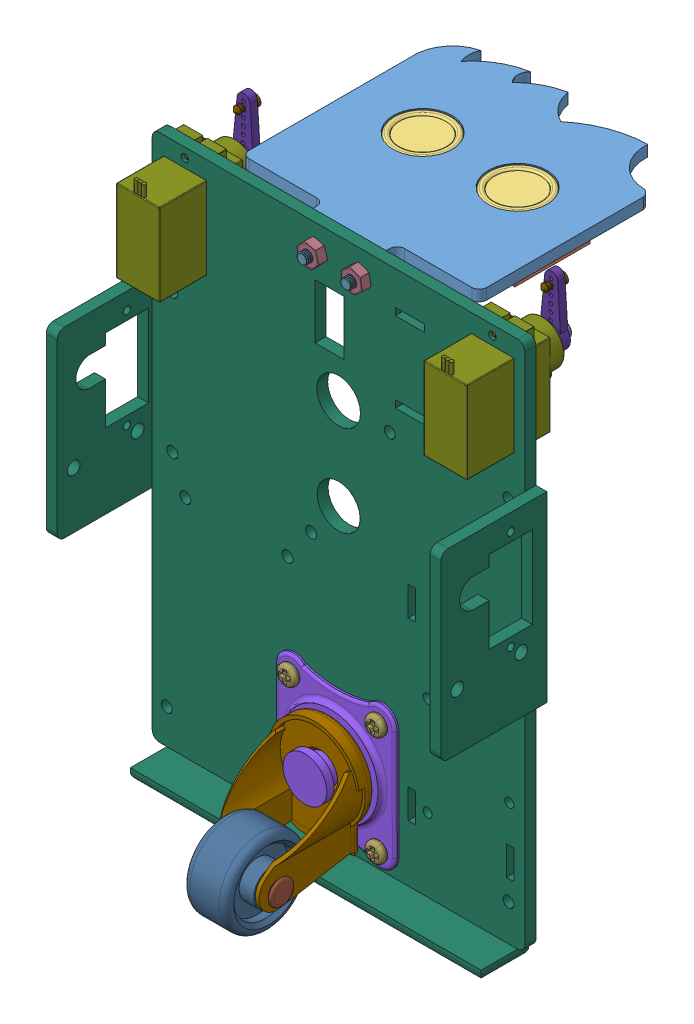
SolidWorks assembly DYOR_3D_PU, configuration Predeterminado. Lengths in mm.
Overall size (108 155.56 103.03).
48 component instances, 19 part files, 12 mates.
Components (placement in the parent):
- Front-1: Front [Predeterminado] at (30.3569 39.5388 1.4932) x (1 0 0) z (0 1 0) size (65 62.44 11)
- HC-SR04 Ping Sensor-1: HC-SR04 Ping Sensor [Default] at (9.418 28.7888 -23.4611) x (0 0 -1) z (0 1 0) size (25.18 45 18.07)
  - PCB-1: PCB [Default] at origin size (20.5 45 1.75)
  - Transducer-1: Transducer [Default] at (0 -13 13.25) x (1 0 0) z (0 -1 0) size (15.88 12 15.88)
  - Transducer-2: Transducer [Default] at (0 13 13.25) x (1 0 0) z (0 -1 0) size (15.88 12 15.88)
  - 3 Pin Header 90 Degree-1: 3 Pin Header 90 Degree [Default] at (8.4275 0 -1.25) x (-1 0 0) z (0 -1 0) size (8 7.82 10)
  - 14 Pin SMT-1: 14 Pin SMT [Default] at (-0.35 -18.5 -0.85) x (0 -1 0) z (1 0 0) size (6 1.6 8.8)
  - 14 Pin SMT-2: 14 Pin SMT [Default] at (0 -0.3826 -0.85) x (1 0 0) z (0 1 0) size (6 1.6 8.8)
  - 14 Pin SMT-3: 14 Pin SMT [Default] at (0 17.5274 -0.85) x (1 0 0) z (0 1 0) size (6 1.6 8.8)
  - Cap1 SMT-1: Cap1 SMT [Default] at (-1.755 7.4774 -0.9689) x (0 1 0) z (-1 0 0) size (4.5 1.84 1.75)
  - Cap1 SMT-2: Cap1 SMT [Default] at (6.835 7.4774 -0.9689) x (0 1 0) z (-1 0 0) size (4.5 1.84 1.75)
  - Cap1 SMT-3: Cap1 SMT [Default] at (-6.835 7.4774 -0.9689) x (0 1 0) z (-1 0 0) size (4.5 1.84 1.75)
  - Cap1 SMT-4: Cap1 SMT [Default] at (4.295 7.4774 -0.9689) x (0 1 0) z (-1 0 0) size (4.5 1.84 1.75)
  - Cap1 SMT-5: Cap1 SMT [Default] at (1.755 7.4774 -0.9689) x (0 1 0) z (-1 0 0) size (4.5 1.84 1.75)
  - Cap1 SMT-6: Cap1 SMT [Default] at (-4.295 7.4774 -0.9689) x (0 1 0) z (-1 0 0) size (4.5 1.84 1.75)
  - HC-SR04 Crystal-1: HC-SR04 Crystal [Default] at (-8.3 0 1.75) x (0 -1 0) z (0 0 1) size (10 3.5 2.7)
- CA-1: CA [Predeterminado] at (-2.2402 -1.1323 0) x (1 0.000939 0) z (0 0 1) size (33 45.94 43.2)
  - Caster Wheel-1: Caster Wheel [Default] at (57.6387 -78.841 57.7572) x (0 1 0) z (-1 0 0) size (45.94 37.59 33)
    - caster holder-1: caster holder [Default] at (-24.0751 44.7184 29.5137) x (1 0 0) z (0 0 -1) size (39 9.27 33)
    - holder-1: holder [Default] at (-1.5751 42.9484 46.0137) x (0 0 1) z (1 0 0) size (25 28.07 31.31)
    - caster wheel-1: caster wheel [Default] at (-15.6961 19.9484 46.0137) x (0.997275 0.073773 0) z (0 0 1) size (23 23 14)
    - Part4-1: Part4 [Default] at (-15.6961 19.9484 55.0137) x (-0.978448 0.206495 0) z (0 0 -1) size (7 7 20)
  - M3x6 Philips Screw-1: M3x6 Philips Screw [Predeterminado] at (23.625 -65.4161 13.5389) size (5.3 5.3 7.81)
  - M3x6 Philips Screw-2: M3x6 Philips Screw [Predeterminado] at (-0.375 -65.4161 13.5389) size (5.3 5.3 7.81)
  - M3x6 Philips Screw-3: M3x6 Philips Screw [Predeterminado] at (-0.375 -95.4161 13.5389) size (5.3 5.3 7.81)
  - M3x6 Philips Screw-4: M3x6 Philips Screw [Predeterminado] at (23.625 -95.4161 13.5389) size (5.3 5.3 7.81)
  - M3 Nut-1: M3 Nut [Predeterminado] at (23.625 -65.4161 11.0389) size (6.27 6.27 2.71)
  - M3 Nut-2: M3 Nut [Predeterminado] at (-0.375 -65.4161 11.0389) size (6.27 6.27 2.71)
  - M3 Nut-3: M3 Nut [Predeterminado] at (-0.375 -95.4161 11.0389) size (6.27 6.27 2.71)
  - M3 Nut-4: M3 Nut [Predeterminado] at (23.625 -95.4161 11.0389) size (6.27 6.27 2.71)
- M3x10 Philips Screw-2: M3x10 Philips Screw [Predeterminado] at (3.418 36.0388 6.5389) x (0.88719 -0.461404 0) z (0 0 -1) size (5.3 5.3 11.8)
- M3x10 Philips Screw-3: M3x10 Philips Screw [Predeterminado] at (15.418 36.0388 6.5389) x (0.471193 -0.88203 0) z (0 0 -1) size (5.3 5.3 11.8)
- M3 Nut-1: M3 Nut [Predeterminado] at (3.418 36.0388 16.5389) x (0.222076 0.975029 0) z (0 0 1) size (6.27 6.27 2.71)
- M3 Nut-2: M3 Nut [Predeterminado] at (15.418 36.0388 11.0389) x (-0.334718 -0.942319 0) z (0 0 -1) size (6.27 6.27 2.71)
- BasePU-1: BasePU [Predeterminado] at (-51.2528 96.5598 9.5389) size (108 147.56 29)
- PU-1: PU [Predeterminado] at (-155.9776 204.2742 -130.283) size (95.94 37.23 33.31)
  - sg90-1: sg90 [Default] at (201.5956 -166.7354 155.7219) x (0 -1 0) z (1 0 0) size (31.9 29.9 11.8)
  - sg90-2: sg90 [Default] at (117.452 -166.7354 155.7219) x (0 -1 0) z (1 0 0) size (31.9 29.9 11.8)
  - SG90 plastic Horn-1: SG90 plastic Horn [Default] at (123.352 -172.6354 127.0219) x (0.017141 0.999853 0) z (-0.999853 0.017141 0) size (19.4 4 7.07)
  - SG90 plastic Horn-2: SG90 plastic Horn [Default] at (207.4956 -172.6354 127.0219) x (0.020276 0.999794 0) z (-0.999794 0.020276 0) size (19.4 4 7.07)
  - M2x6 SelfTap Screw-1: M2x6 SelfTap Screw [Predeterminado] at (207.4956 -164.3354 136.8219) x (-0.923728 -0.383049 0) z (0 0 -1) size (3.4 3.28 6)
  - M2x6 SelfTap Screw-2: M2x6 SelfTap Screw [Predeterminado] at (207.4956 -191.6354 136.3219) x (-0.923728 -0.383049 0) z (0 0 -1) size (3.4 3.28 6)
  - M2x6 SelfTap Screw-3: M2x6 SelfTap Screw [Predeterminado] at (123.352 -164.3354 136.8219) x (-0.993348 0.115149 0) z (0 0 -1) size (3.4 3.28 6)
  - M2x6 SelfTap Screw-4: M2x6 SelfTap Screw [Predeterminado] at (123.352 -191.6354 136.8219) x (-0.923728 -0.383049 0) z (0 0 -1) size (3.4 3.28 6)
  - (M2_3_mm)_90116A007_METRIC 316 SS PAN HEAD PHILLIPS MACHINE SCREW-1: (M2_3_mm)_90116A007_METRIC 316 SS PAN HEAD PHILLIPS MACHINE SCREW [90116A007] at (123.352 -172.6354 127.0219) x (-0.923728 -0.383049 0) z (0 0 -1) size (4 4 4.68)
  - (M2_3_mm)_90116A007_METRIC 316 SS PAN HEAD PHILLIPS MACHINE SCREW-2: (M2_3_mm)_90116A007_METRIC 316 SS PAN HEAD PHILLIPS MACHINE SCREW [90116A007] at (207.4956 -172.6354 127.0219) x (-0.923728 -0.383049 0) z (0 0 -1) size (4 4 4.68)
  - M2x6 SelfTap Screw-5: M2x6 SelfTap Screw [Predeterminado] at (123.352 -160.1354 123.5219) x (-0.923728 -0.383049 0) z (0 0 -1) size (3.4 3.28 6)
  - M2x6 SelfTap Screw-6: M2x6 SelfTap Screw [Predeterminado] at (207.4956 -160.1354 123.5219) x (-0.923728 -0.383049 0) z (0 0 -1) size (3.4 3.28 6)
Mates (geometry in assembly coordinates):
- Concéntrica4: concentric: circle of Front-1; circle of HC-SR04 Ping Sensor-1/Transducer-1
- Concéntrica5: concentric: circle of Front-1; circle of HC-SR04 Ping Sensor-1/Transducer-2
- Coincidente3: coincident: plane of Front-1 through (-2.582 42.5388 8.5374) normal (0 1 0); plane of HC-SR04 Ping Sensor-1/Transducer-1 through (22.418 42.5388 -31.4011) normal (0 1 0)
- Coincidente12: coincident: plane of Front-1 through (-0.582 42.5388 9.5389) normal (0 0 1); plane of BasePU-1 through (58.418 40.5388 9.5389) normal (0 0 -1)
- Concéntrica15: concentric: circle of M3 Nut-2; circle of BasePU-1
- Coincidente13: coincident: plane of Front-1 through (-0.582 31.5388 6.5389) normal (0 0 -1); plane of M3x10 Philips Screw-3 through (14.0068 35.2849 6.5389) normal (0 0 1)
- Coincidente14: coincident: plane of Front-1 through (-0.582 31.5388 6.5389) normal (0 0 -1); plane of M3x10 Philips Screw-2 through (2.6798 34.6193 6.5389) normal (0 0 1)
- Coincidente15: coincident: plane of M3 Nut-1 through (3.418 36.0388 12.5389) normal (0 0 -1); plane of BasePU-1 through (58.418 40.5388 12.5389) normal (0 0 1)
- Coincidente16: coincident: plane of M3 Nut-2 through (15.418 36.0388 12.5389) normal (0 0 -1); plane of BasePU-1 through (58.418 40.5388 12.5389) normal (0 0 1)
- Coincidente17: coincident: plane of BasePU-1 through (57.418 37.5388 12.5389) normal (0 -1 0); plane of PU-1/sg90-1 through (57.418 37.5388 25.4389) normal (0 1 0)
- Coincidente18: coincident: plane of BasePU-1 through (58.418 40.5388 9.5389) normal (0 0 -1); plane of PU-1/sg90-1 through (57.418 10.3388 9.5389) normal (0 0 1)
- Concéntrica16: concentric: circle of BasePU-1; circle of PU-1/M2x6 SelfTap Screw-2
